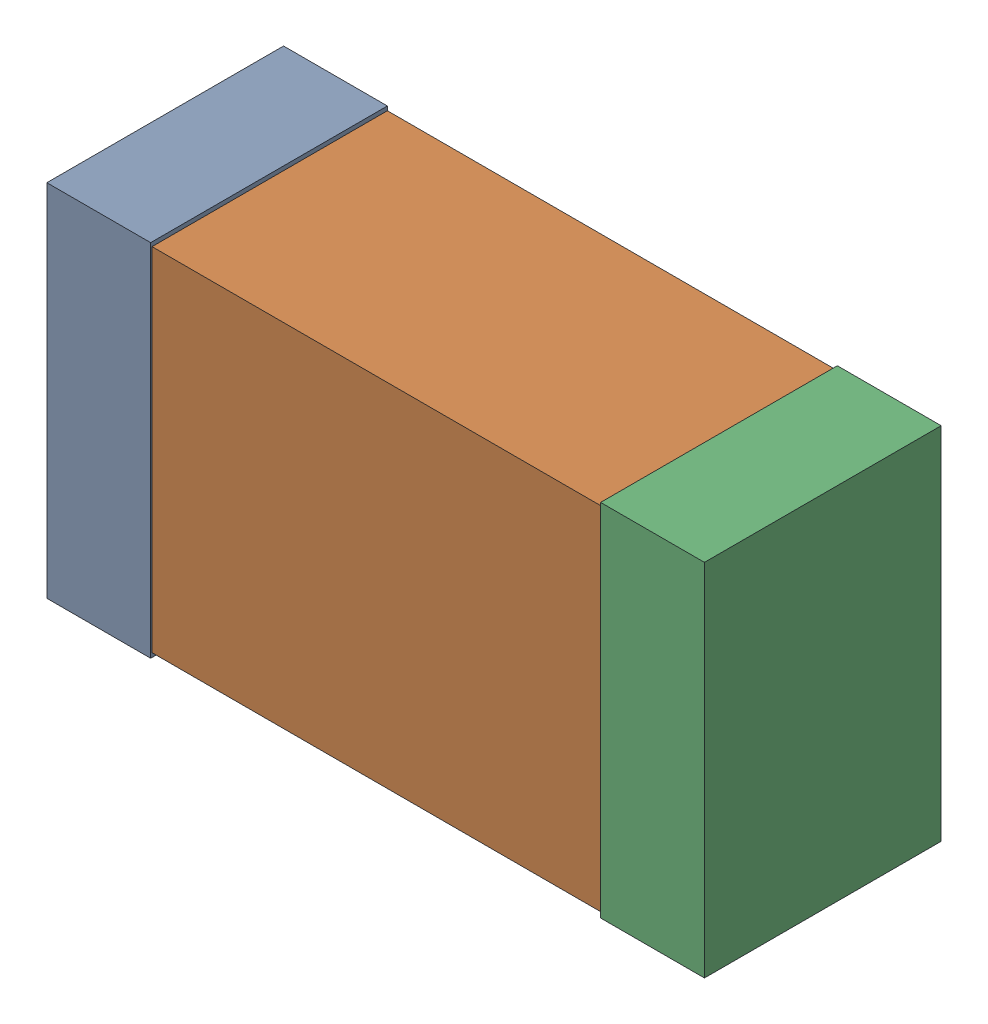
SolidWorks assembly C6Kanaloa_v2.0.0_GPIO_b, configuration Default. Lengths in mm.
Overall size (2.38 1.3 0.85).
6 component instances, 2 part files, 0 mates.
Components (placement in the parent):
- 352877648-1: 352877648 [Default] at (82.185 50.292 0) size (0.38 1.3 0.85)
  - Extruded_14-1: Extruded_14 [Default] at origin size (0.38 1.3 0.85)
- 352877904-1: 352877904 [Default] at (83.185 50.292 0) size (2.2 1.27 0.85)
  - Extruded_18-1: Extruded_18 [Default] at origin size (2.2 1.27 0.85)
- 352877648-2: 352877648 [Default] at (84.185 50.292 0) size (0.38 1.3 0.85)
  - Extruded_14-1: Extruded_14 [Default] at origin size (0.38 1.3 0.85)
